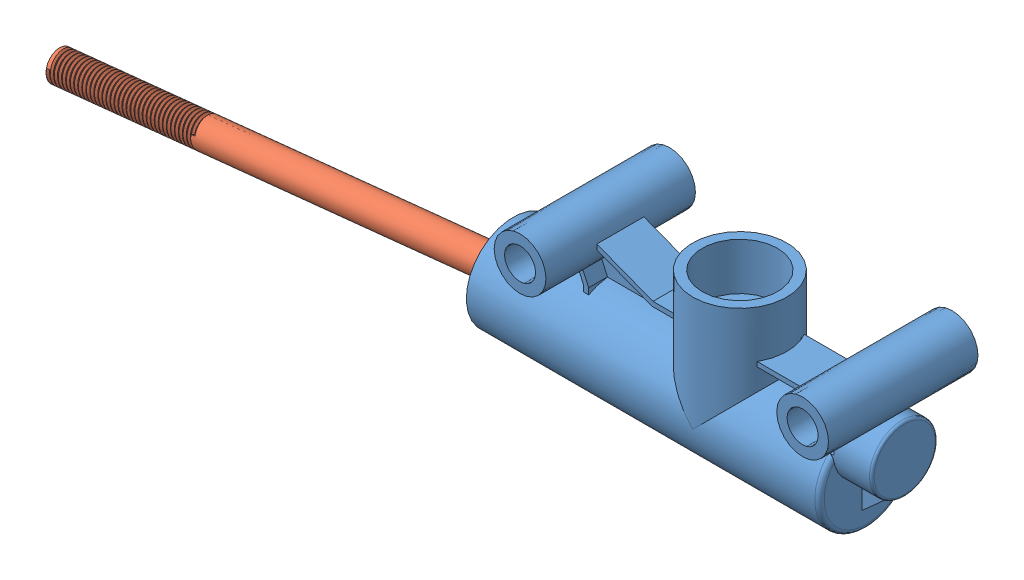
SolidWorks assembly SideMountWilwoodMC, configuration Default. Lengths in mm.
Overall size (224.46 45.29 40.32).
2 component instances, 2 part files, 2 mates.
Components (placement in the parent):
- NewWilwoodMasterCylinder-1: NewWilwoodMasterCylinder [Default] at origin size (105.52 43.57 40.32)
- MCpushrod-1: MCpushrod [Default] at (-75.1401 15.5283 -4.8032) x (0.99655 0.077514 -0.029658) z (-0.003898 -0.313248 -0.949663) size (121.55 7.94 7.94)
Mates (geometry in assembly coordinates):
- Coincident4: coincident: line of NewWilwoodMasterCylinder-1 through (6.35 0 0) axis (1 0 0); point of MCpushrod-1
- LimitDistance4: limit distance = 0 mm: plane of assembly; point of MCpushrod-1; plane of NewWilwoodMasterCylinder-1 through (2.54 0 0) normal (-1 0 0)
